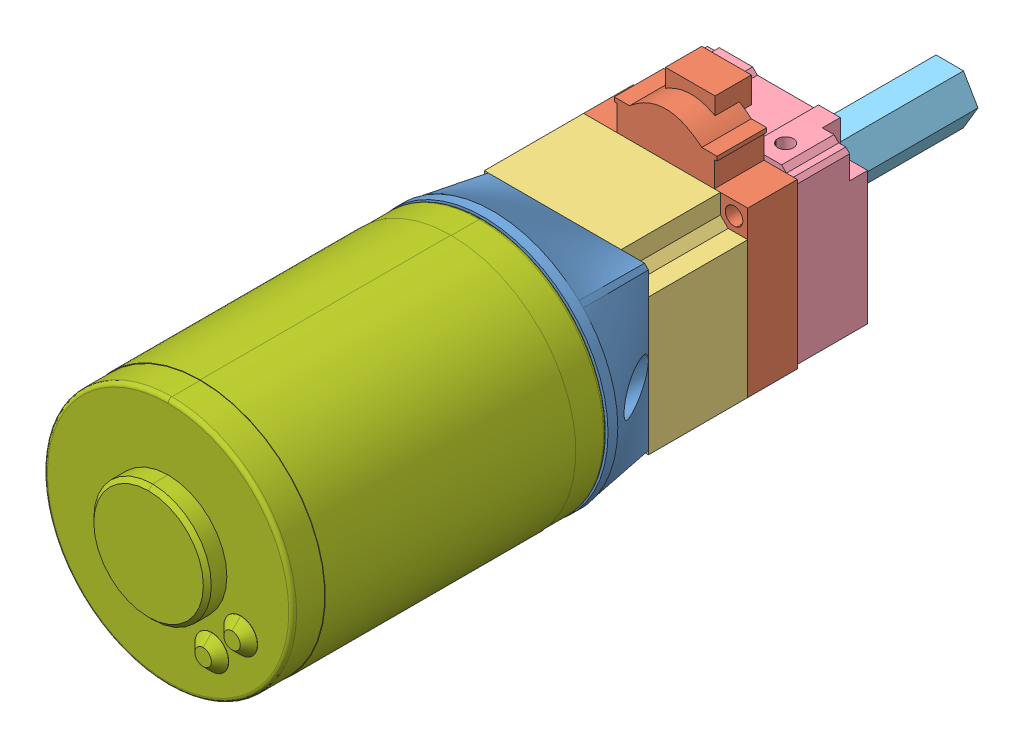
SolidWorks assembly CIM motor assembled with encoder, configuration Default. Lengths in mm.
Overall size (64.1 67.24 205.05).
7 component instances, 7 part files, 18 mates.
Components (placement in the parent):
- CIM adapter-1: CIM adapter [Default] at (0 0 18.85) x (-1 0 0) z (0 0 1) size (64.1 64.1 21.35)
- Integrated encoder-1: Integrated encoder [Default] at (0 0 -25.4) x (0 -1 0) z (0 0 -1) size (56.19 42 17.3)
- Gearbox mid section-1: Gearbox mid section [Default] at (0 0 -25.4) size (42 42 25.4)
- Planetary gearbox attachement to wheel-1: Planetary gearbox attachement to wheel [Default] at (-0.01 0 -38.1) x (1 0 0) z (0 0 -1) size (42.02 44.46 18)
- Hex shaft-1: Hex shaft [Default] at (-0.01 0 -56.1) x (-0.999992 0.003906 0) z (0 0 -1) size (17.5 17.5 42)
- Hex shaft base-1: Hex shaft base [Default] at (-0.01 0 -56.1) x (0.841403 0.540408 0) z (0.540408 -0.841403 0) size (27.6 10 27.6)
- CIM mini motor-1: CIM mini motor [Default] at (0 0 21.35) x (0 0 1) z (0 1 0) size (99.13 64.01 64.01)
Mates (geometry in assembly coordinates):
- Coincident28: coincident aligned: plane of Integrated encoder-1 through (-45.5717 21 -38.1) normal (0 1 0); plane of Gearbox mid section-1 through (-24.5717 21 0) normal (0 1 0)
- Coincident29: coincident aligned: plane of Integrated encoder-1 through (-3.5717 -21 -38.1) normal (1 0 0); plane of Gearbox mid section-1 through (-3.5717 21 0) normal (1 0 0)
- Coincident36: coincident aligned: plane of Gearbox mid section-1 through (-3.5717 21 0) normal (1 0 0); plane of Planetary gearbox attachement to wheel-1 through (-3.5717 -20 -56.1) normal (1 0 0)
- Coincident37: coincident aligned: plane of Gearbox mid section-1 through (-24.5717 21 0) normal (0 1 0); plane of Planetary gearbox attachement to wheel-1 through (-31.7817 21 -56.1) normal (0 1 0)
- Concentric6: concentric aligned: cylinder of Planetary gearbox attachement to wheel-1 through (-24.5817 0 -68.1) axis (0 0 1) radius 13.8; cylinder of Hex shaft-1 through (-24.5817 0 -58.1) axis (0 0 1) radius 8.75
- Coincident39: coincident anti-aligned: plane of Planetary gearbox attachement to wheel-1 through (-24.5817 0 -56.1) normal (0 0 -1); plane of Hex shaft-1 through (-24.5817 0 -56.1) normal (0 0 1)
- Concentric8: concentric anti-aligned: cylinder of Planetary gearbox attachement to wheel-1 through (-24.5817 0 -68.1) axis (0 0 1) radius 13.8; cylinder of Hex shaft base-1 through (-24.5817 0 -46.1) axis (0 0 -1) radius 13.8
- Coincident41: coincident aligned: plane of Planetary gearbox attachement to wheel-1 through (-24.5817 0 -56.1) normal (0 0 -1); plane of Hex shaft base-1 through (-24.5817 0 -56.1) normal (0 0 -1)
- Coincident42: coincident anti-aligned: plane of CIM adapter-1 through (-24.5717 0 0) normal (0 0 -1)
- Coincident43: coincident anti-aligned: plane of CIM adapter-1 through (-24.5717 0 21.35) normal (0 0 1); plane of CIM mini motor-1 through (-15.0467 0 21.35) normal (0 0 -1)
- Concentric9: concentric aligned: cylinder of CIM adapter-1 through (0.8283 0 19.35) axis (0 0 -1) radius 4.35; cylinder of CIM mini motor-1 through (0.8283 0 21.35) axis (0 0 -1) radius 2.0193
- Concentric10: concentric anti-aligned: cylinder of CIM adapter-1 through (-24.5717 0 21.35) axis (0 0 -1) radius 32; cylinder of CIM mini motor-1 through (-24.5717 0 21.35) axis (0 0 1) radius 32.004
- Coincident44: coincident anti-aligned: plane of Integrated encoder-1 through (-24.5717 0 -38.1) normal (0 0 -1); plane of Planetary gearbox attachement to wheel-1 through (-24.5817 0 -38.1) normal (0 0 1)
- Coincident45: coincident anti-aligned: plane of Integrated encoder-1 through (-24.5717 0 -25.4) normal (0 0 1); plane of Gearbox mid section-1 through (-24.5717 0 -25.4) normal (0 0 -1)
- Coincident46: coincident anti-aligned: plane of CIM adapter-1 through (-24.5717 0 0) normal (0 0 -1); plane of Gearbox mid section-1 through (-24.5717 0 0) normal (0 0 1)
- Concentric11: concentric anti-aligned: cylinder of CIM adapter-1 through (-24.5717 0 16.35) axis (0 0 -1) radius 12.725; cylinder of Gearbox mid section-1 through (-24.5717 0 -25.4) axis (0 0 1) radius 18.8
- Coincident47: coincident aligned: plane of CIM mini motor-1 through (-24.5717 0 21.35) normal (0 1 0)
- Coincident48: coincident aligned: plane of CIM mini motor-1 through (0 0 21.35) normal (1 0 0)
